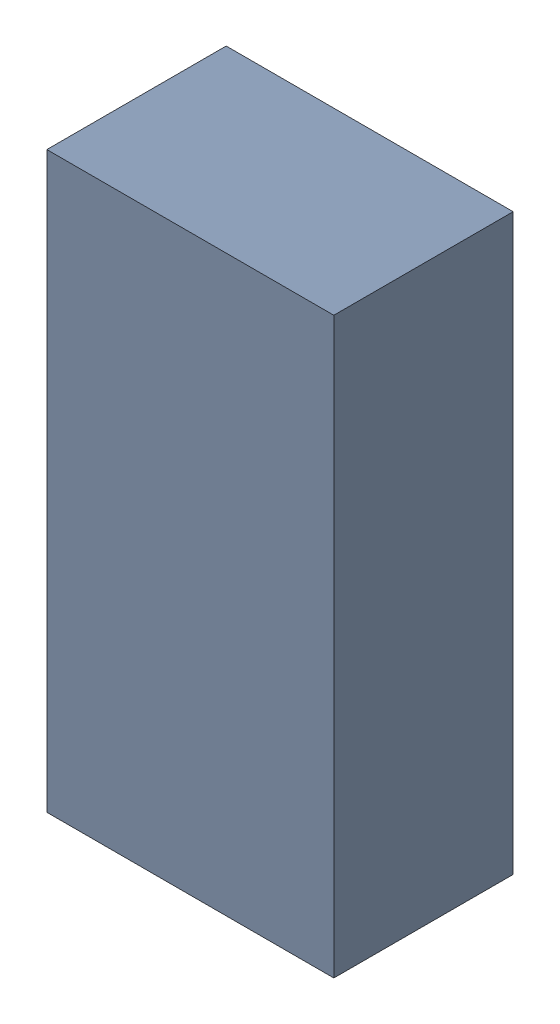
SolidWorks assembly R300_1PCB, configuration Default. Lengths in mm.
Overall size (1.6 3.2 1).
2 component instances, 1 part files, 0 mates.
Components (placement in the parent):
- 846485328-1: 846485328 [Default] at (156.3001 109.3001 0) size (1.6 3.2 1)
  - Extruded_34-1: Extruded_34 [Default] at origin size (1.6 3.2 1)
